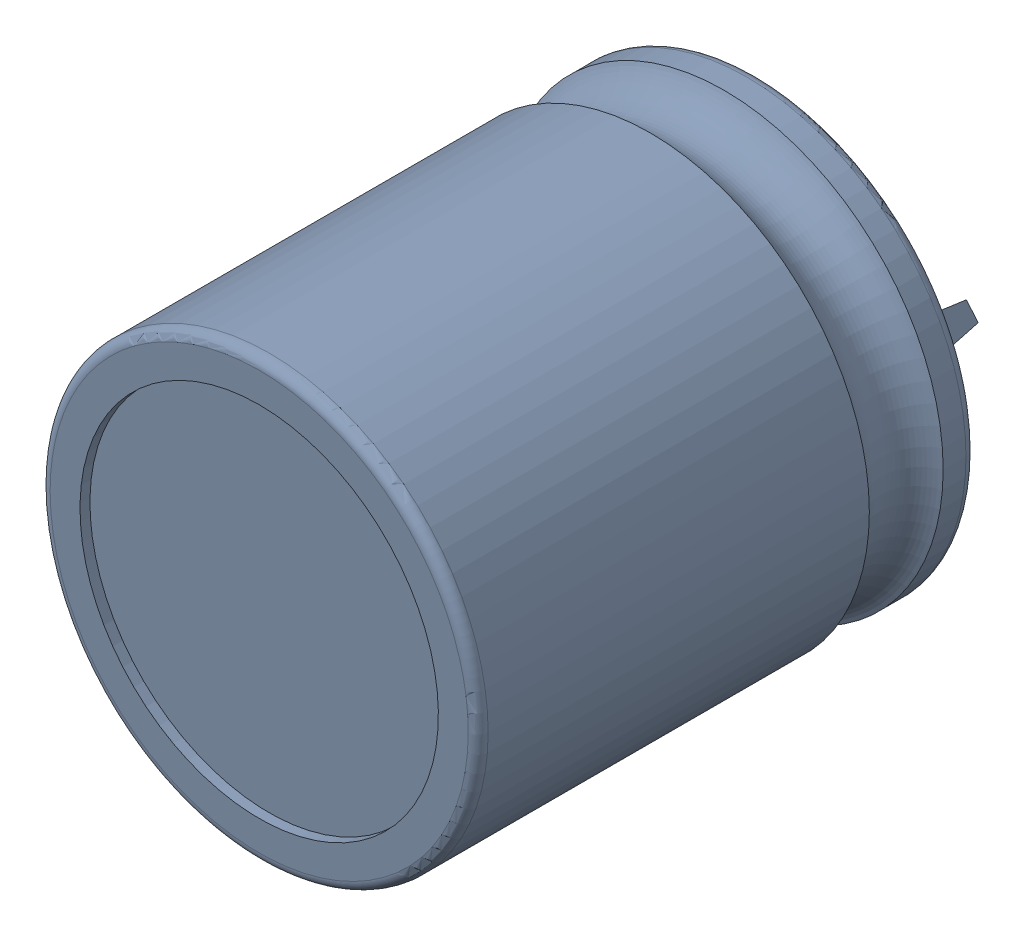
SolidWorks assembly C3, configuration Default. Lengths in mm.
Overall size (22 22 31.01).
4 component instances, 2 part files, 0 mates.
Components (placement in the parent):
- Capacitor22x25-1: Capacitor22x25 [Default] at (131.8111 69.5138 -3.686) x (1 0 0) z (0 -1 0) size (22 31.01 22)
  - User_Library-ECEC2DP271BJ-1: User_Library-ECEC2DP271BJ [Default] at (8.9531 3.6858 17.317) size (22 25.01 22)
  - User_Library-CAP_EL_SNAP-IN_10_35x45_Valor_predeterminado-1: User_Library-CAP_EL_SNAP-IN_10_35x45_Valor_predeterminado [Default] at (14.4607 11.8368 29.4898) x (0.642788 0 0.766044) z (-0.766044 0 0.642788) size (3.5 7.01 5.68)
  - User_Library-CAP_EL_SNAP-IN_10_35x45_Valor_predeterminado-2: User_Library-CAP_EL_SNAP-IN_10_35x45_Valor_predeterminado [Default] at (2.8917 11.8368 4.8301) x (-0.67559 0 -0.737277) z (0.737277 0 -0.67559) size (3.5 7.01 5.68)
